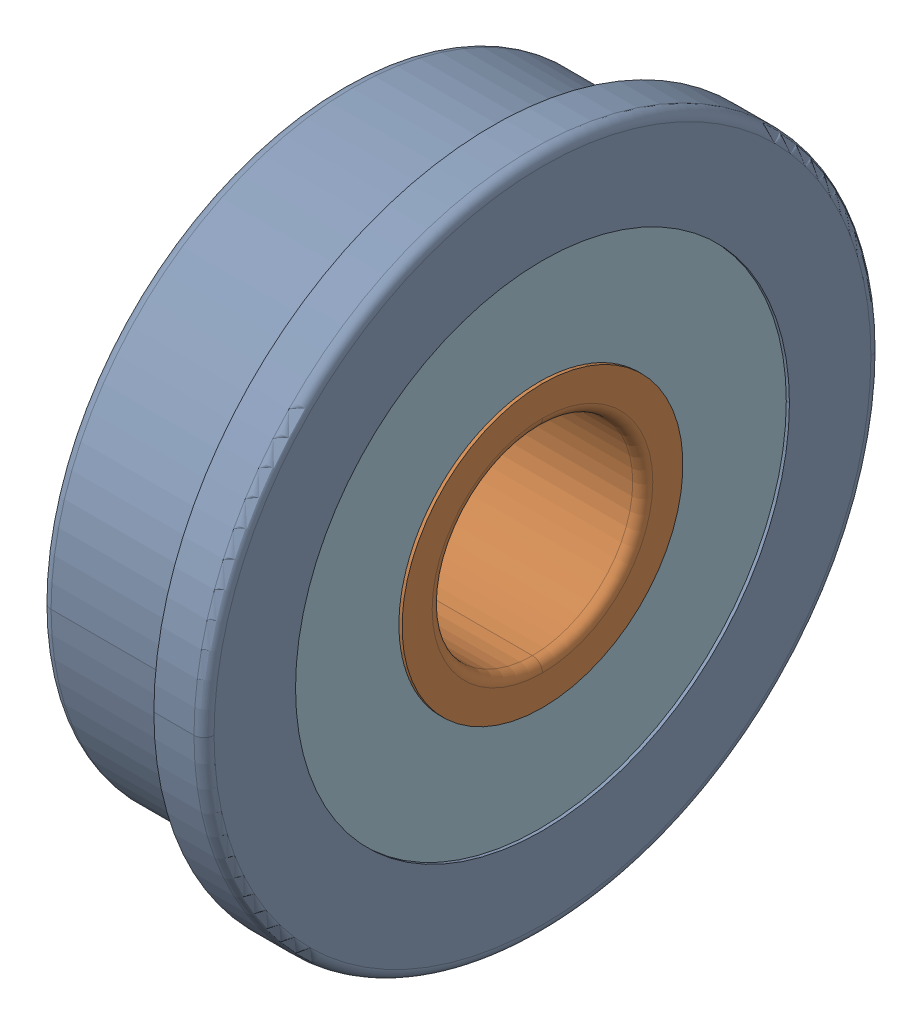
SolidWorks assembly F604ZZ, configuration Default. Lengths in mm.
Overall size (4 13.5 13.5).
12 component instances, 5 part files, 0 mates.
Components (placement in the parent):
- _F604ZZ_Outer_Ring_2-1: _F604ZZ_Outer_Ring_2 [Default] at origin size (4 13.5 13.5)
- _F604ZZ_Inner_Ring_4-1: _F604ZZ_Inner_Ring_4 [Default] x (1 0 0) z (0 -1 0) size (4 6.15 6.15)
- _F604ZZ_Shield1_6-1: _F604ZZ_Shield1_6 [Default] at (0.5 0 0) x (-1 0 0) z (0 -1 0) size (0.19 9.85 9.85)
- _F604ZZ_Ball_8-1: _F604ZZ_Ball_8 [Default] at (2 0 4) x (1 0 0) z (0 -1 0) size (2.4 2.4 2.4)
- _F604ZZ_Ball_8-2: _F604ZZ_Ball_8 [Default] at (2 -2.8284 2.8284) x (1 0 0) z (0 -1 0) size (2.4 2.4 2.4)
- _F604ZZ_Ball_8-3: _F604ZZ_Ball_8 [Default] at (2 -4 0) x (1 0 0) z (0 -1 0) size (2.4 2.4 2.4)
- _F604ZZ_Ball_8-4: _F604ZZ_Ball_8 [Default] at (2 -2.8284 -2.8284) x (1 0 0) z (0 -1 0) size (2.4 2.4 2.4)
- _F604ZZ_Ball_8-5: _F604ZZ_Ball_8 [Default] at (2 0 -4) x (1 0 0) z (0 -1 0) size (2.4 2.4 2.4)
- _F604ZZ_Ball_8-6: _F604ZZ_Ball_8 [Default] at (2 2.8284 -2.8284) x (1 0 0) z (0 -1 0) size (2.4 2.4 2.4)
- _F604ZZ_Ball_8-7: _F604ZZ_Ball_8 [Default] at (2 4 0) x (1 0 0) z (0 -1 0) size (2.4 2.4 2.4)
- _F604ZZ_Ball_8-8: _F604ZZ_Ball_8 [Default] at (2 2.8284 2.8284) x (1 0 0) z (0 -1 0) size (2.4 2.4 2.4)
- _F604ZZ_Shield2_17-1: _F604ZZ_Shield2_17 [Default] at origin size (0.19 9.85 9.85)
